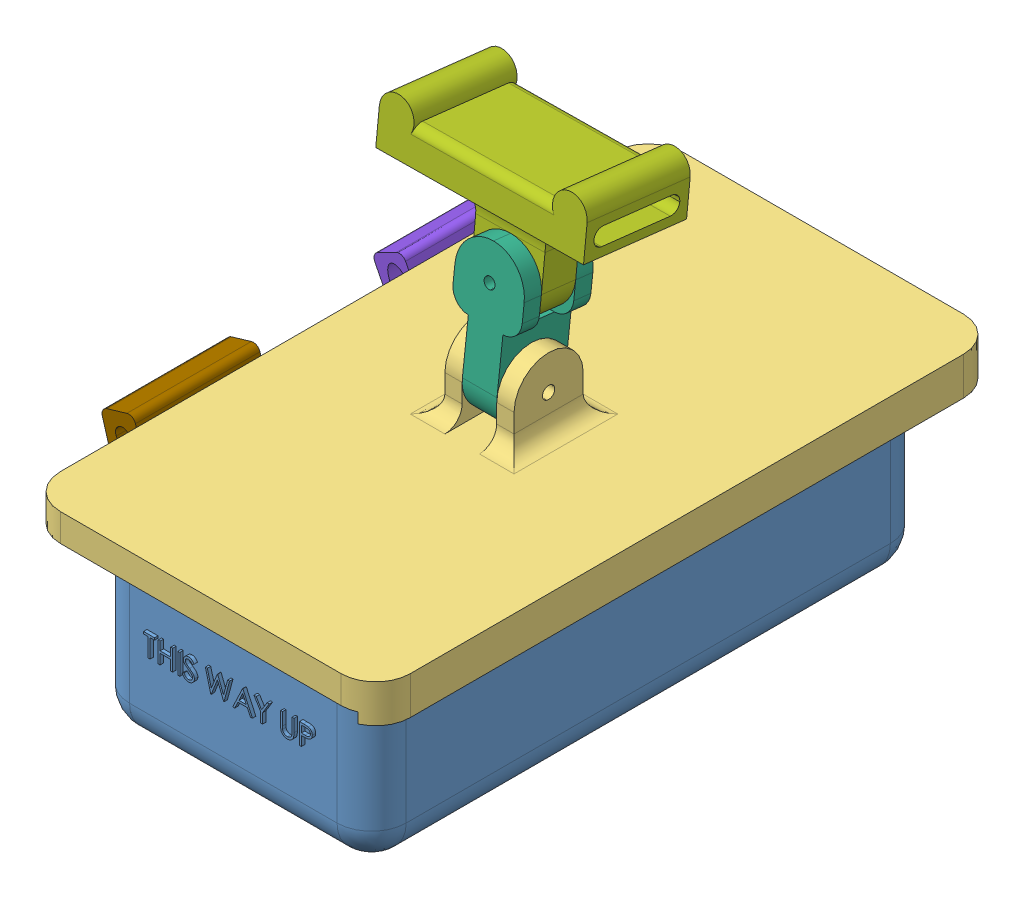
SolidWorks assembly Enclosure_2, configuration Default. Lengths in mm.
Overall size (143.75 176.14 228.6).
95 component instances, 27 part files, 36 mates.
Components (placement in the parent):
- Case-2: Case [Default] at (-101.6 0 -203.2) x (0 0 1) z (0 1 0) size (222.25 128.91 71.12)
- Battery Mockup-1: Battery Mockup [Default] at (-90.805 45.72 -177.165) x (0 0 1) z (-1 0 0) size (171.45 22.86 80.01)
- Lid-1: Lid [Default] at (14.2 73.66 12.7) x (-1 0 0) z (0 0 1) size (133.58 39.88 228.6)
- Camera Bracket-1: Camera Bracket [Default] at (-25.4 2.54 -66.675) x (0 0 -1) z (1 0 0) size (50.8 7.62 50.8)
- Separator-1: Separator [Default] at (-3.175 45.72 -3.175) x (0 -1 0) z (1 0 0) size (2.54 196.85 95.25)
- Cam V2.1 v1.step-1: Cam V2.1 v1.step [Default] at (-51.73 11.16 -89.4159) x (0 -1 0) z (1 0 0) size (6.48 24.01 25.01)
- RapberryPiZero.STEP-1: RapberryPiZero.STEP [Default] at (-102.4814 -13.0566 -128.6208) x (-1 0 0) z (0 0 -1) size (65 4.45 31.23)
  - Raspberry_pizero_PCB.STEP-1: Raspberry_pizero_PCB.STEP [Default] at (-51.2564 20.0966 13.0542) size (65 1 30)
  - Micro USB_input_female (short)-SMT.STEP-1: Micro USB_input_female (short)-SMT.STEP [Default] at (-42.3564 22.3216 26.5042) size (7.98 2.94 5.43)
  - Micro USB_input_female (short)-SMT.STEP-2: Micro USB_input_female (short)-SMT.STEP [Default] at (-29.7564 22.3216 26.5042) size (7.98 2.94 5.43)
  - 0204 - Capacitor.STEP-1: 0204 - Capacitor.STEP [Default] at (-62.4121 21.3466 11.2398) size (1 0.5 0.6)
  - 0204 - Capacitor.STEP-2: 0204 - Capacitor.STEP [Default] at (-62.4121 21.3466 12.2528) size (1 0.5 0.6)
  - 0204 - Capacitor.STEP-3: 0204 - Capacitor.STEP [Default] at (-61.8122 21.3466 13.3136) size (1 0.5 0.6)
  - 0204 - Capacitor.STEP-4: 0204 - Capacitor.STEP [Default] at (-61.8122 21.3466 14.2646) size (1 0.5 0.6)
  - 0204 - Capacitor.STEP-5: 0204 - Capacitor.STEP [Default] at (-61.8122 21.3466 15.241) size (1 0.5 0.6)
  - 0204 - Capacitor.STEP-6: 0204 - Capacitor.STEP [Default] at (-61.8122 21.3466 16.2144) size (1 0.5 0.6)
  - 0204 - Capacitor.STEP-7: 0204 - Capacitor.STEP [Default] at (-61.8122 21.3466 17.2416) size (1 0.5 0.6)
  - 0204 - Capacitor.STEP-8: 0204 - Capacitor.STEP [Default] at (-62.5919 21.3466 20.9695) size (1 0.5 0.6)
  - 0204 - Capacitor.STEP-9: 0204 - Capacitor.STEP [Default] at (-62.5919 21.3466 21.919) size (1 0.5 0.6)
  - 0204 - Capacitor.STEP-10: 0204 - Capacitor.STEP [Default] at (-60.4584 21.3466 22.3712) x (0 0 1) z (-1 0 0) size (1 0.5 0.6)
  - 0204 - Capacitor.STEP-11: 0204 - Capacitor.STEP [Default] at (-60.0807 21.3466 22.3712) x (0 0 -1) z (1 0 0) size (1 0.5 0.6)
  - 0204 - Capacitor.STEP-12: 0204 - Capacitor.STEP [Default] at (-59.0466 21.3466 22.3712) x (0 0 -1) z (1 0 0) size (1 0.5 0.6)
  - 0204 - Capacitor.STEP-13: 0204 - Capacitor.STEP [Default] at (-52.6496 21.3466 22.316) x (0 0 1) z (-1 0 0) size (1 0.5 0.6)
  - 0204 - Capacitor.STEP-14: 0204 - Capacitor.STEP [Default] at (-52.25 21.3466 22.316) x (0 0 -1) z (1 0 0) size (1 0.5 0.6)
  - 0204 - Capacitor.STEP-15: 0204 - Capacitor.STEP [Default] at (-51.2398 21.3466 22.316) x (0 0 -1) z (1 0 0) size (1 0.5 0.6)
  - 0204 - Capacitor.STEP-16: 0204 - Capacitor.STEP [Default] at (-49.1841 21.3466 22.316) x (0 0 -1) z (1 0 0) size (1 0.5 0.6)
  - 0204 - Capacitor.STEP-17: 0204 - Capacitor.STEP [Default] at (-48.1448 21.3466 22.316) x (0 0 -1) z (1 0 0) size (1 0.5 0.6)
  - 0204 - Capacitor.STEP-18: 0204 - Capacitor.STEP [Default] at (-46.475 21.3466 21.113) size (1 0.5 0.6)
  - 0204 - Capacitor.STEP-19: 0204 - Capacitor.STEP [Default] at (-45.7322 21.3466 20.0663) size (1 0.5 0.6)
  - 0204 - Capacitor.STEP-20: 0204 - Capacitor.STEP [Default] at (-45.7322 21.3466 19.0675) size (1 0.5 0.6)
  - 0204 - Capacitor.STEP-21: 0204 - Capacitor.STEP [Default] at (-45.7322 21.3466 18.1249) size (1 0.5 0.6)
  - 0204 - Capacitor.STEP-22: 0204 - Capacitor.STEP [Default] at (-45.7322 21.3466 17.1095) size (1 0.5 0.6)
  - 0204 - Capacitor.STEP-23: 0204 - Capacitor.STEP [Default] at (-46.3457 21.3466 16.1412) size (1 0.5 0.6)
  - 0204 - Capacitor.STEP-24: 0204 - Capacitor.STEP [Default] at (-46.3457 21.3466 15.1229) size (1 0.5 0.6)
  - 0204 - Capacitor.STEP-25: 0204 - Capacitor.STEP [Default] at (-46.3457 21.3466 14.0197) size (1 0.5 0.6)
  - 0204 - Capacitor.STEP-26: 0204 - Capacitor.STEP [Default] at (-46.3457 21.3466 12.9589) size (1 0.5 0.6)
  - 0204 - Capacitor.STEP-27: 0204 - Capacitor.STEP [Default] at (-43.6156 21.3466 13.1418) size (1 0.5 0.6)
  - 0204 - Capacitor.STEP-28: 0204 - Capacitor.STEP [Default] at (-43.6156 21.3466 10.1424) size (1 0.5 0.6)
  - 0204 - Capacitor.STEP-29: 0204 - Capacitor.STEP [Default] at (-48.9117 21.3466 7.6917) size (1 0.5 0.6)
  - 0204 - Capacitor.STEP-30: 0204 - Capacitor.STEP [Default] at (-55.4926 21.3466 7.2526) x (0 0 -1) z (1 0 0) size (1 0.5 0.6)
  - 0204 - Capacitor.STEP-31: 0204 - Capacitor.STEP [Default] at (-53.7932 21.3466 7.2526) x (0 0 1) z (-1 0 0) size (1 0.5 0.6)
  - 0204 - Capacitor.STEP-32: 0204 - Capacitor.STEP [Default] at (-59.8477 21.3466 7.2526) x (0 0 1) z (-1 0 0) size (1 0.5 0.6)
  - 0204- Resistor.STEP-1: 0204- Resistor.STEP [Default] at (-43.6109 21.4522 15.4193) x (-1 0 0) z (0 -1 0) size (0.99 0.51 0.36)
  - 0204- Resistor.STEP-2: 0204- Resistor.STEP [Default] at (-43.6109 21.4522 14.4127) x (-1 0 0) z (0 -1 0) size (0.99 0.51 0.36)
  - 0204- Resistor.STEP-3: 0204- Resistor.STEP [Default] at (-43.6109 21.4522 12.4047) x (-1 0 0) z (0 -1 0) size (0.99 0.51 0.36)
  - 0204- Resistor.STEP-4: 0204- Resistor.STEP [Default] at (-42.6936 21.4522 18.4076) x (-1 0 0) z (0 -1 0) size (0.99 0.51 0.36)
  - 0204- Resistor.STEP-5: 0204- Resistor.STEP [Default] at (-39.831 21.4522 18.1462) x (0 0 1) z (0 -1 0) size (0.99 0.51 0.36)
  - 0204- Resistor.STEP-6: 0204- Resistor.STEP [Default] at (-61.8169 21.4522 19.8533) x (-1 0 0) z (0 -1 0) size (0.99 0.51 0.36)
  - 0204- Resistor.STEP-7: 0204- Resistor.STEP [Default] at (-61.8169 21.4522 18.5178) x (-1 0 0) z (0 -1 0) size (0.99 0.51 0.36)
  - 0204- Resistor.STEP-8: 0204- Resistor.STEP [Default] at (-79.148 21.4522 17.7279) x (-1 0 0) z (0 -1 0) size (0.99 0.51 0.36)
  - 0204- Resistor.STEP-9: 0204- Resistor.STEP [Default] at (-56.0985 21.4522 7.2479) x (0 0 -1) z (0 -1 0) size (0.99 0.51 0.36)
  - 0204- Resistor.STEP-10: 0204- Resistor.STEP [Default] at (-28.0827 21.4522 9.5819) x (-1 0 0) z (0 -1 0) size (0.99 0.51 0.36)
  - 0204- Resistor.STEP-11: 0204- Resistor.STEP [Default] at (-21.8613 21.4522 20.9026) x (-1 0 0) z (0 -1 0) size (0.99 0.51 0.36)
  - CAP-0306.STEP-1: CAP-0306.STEP [Default] at (-45.8903 21.4966 8.7634) size (1.6 0.8 0.9)
  - CAP-0306.STEP-2: CAP-0306.STEP [Default] at (-82.0031 21.4966 19.0464) x (0 0 1) z (-1 0 0) size (1.6 0.8 0.9)
  - Raspberry_pizero_BCM2835 with VC4.STEP-1: Raspberry_pizero_BCM2835 with VC4.STEP [Default] at (-54.1608 21.5466 15.1238) x (1 0 0) z (0 0 -1) size (12 0.65 12)
  - Crystal 3.4x2.4mm.STEP-1: Crystal 3.4x2.4mm.STEP [Default] at (-65.3089 21.0966 19.2633) size (3.2 1 2.4)
  - 0204- Resistor.STEP-12: 0204- Resistor.STEP [Default] at (-68.4329 21.4522 5.4384) x (0 0 1) z (0 -1 0) size (0.99 0.51 0.36)
  - 0204- Resistor.STEP-13: 0204- Resistor.STEP [Default] at (-69.7255 21.4522 5.4384) x (0 0 1) z (0 -1 0) size (0.99 0.51 0.36)
  - 0204- Resistor.STEP-14: 0204- Resistor.STEP [Default] at (-65.0626 21.4522 16.5355) x (1 0 0) z (0 -1 0) size (0.99 0.51 0.36)
  - 32,768 Khz Crystal.STEP-1: 32,768 Khz Crystal.STEP [Default] at (-60.5154 21.1428 26.5473) x (0.999848 -0.017452 0) z (0 0 1) size (3.4 1.03 1.5)
  - 0805- Capacitor.STEP-1: 0805- Capacitor.STEP [Default] at (-51.9496 21.9966 5.2384) x (1 0 0) z (0 -1 0) size (2 1.26 0.91)
  - 0805- Capacitor.STEP-2: 0805- Capacitor.STEP [Default] at (-51.9496 21.9966 7.3589) x (1 0 0) z (0 -1 0) size (2 1.26 0.91)
  - 0805- Capacitor.STEP-3: 0805- Capacitor.STEP [Default] at (-37.009 21.9966 22.5384) x (0 0 -1) z (0 -1 0) size (2 1.26 0.91)
  - 0805- Capacitor.STEP-4: 0805- Capacitor.STEP [Default] at (-29.8247 21.9966 13.3538) x (0 0 1) z (0 -1 0) size (2 1.26 0.91)
  - 0805- Capacitor.STEP-5: 0805- Capacitor.STEP [Default] at (-27.9052 21.9966 13.3538) x (0 0 -1) z (0 -1 0) size (2 1.26 0.91)
  - 0805- Capacitor.STEP-6: 0805- Capacitor.STEP [Default] at (-22.8003 21.9966 13.3538) x (0 0 -1) z (0 -1 0) size (2 1.26 0.91)
  - 0805- Capacitor.STEP-7: 0805- Capacitor.STEP [Default] at (-20.9924 21.9966 13.3538) x (0 0 -1) z (0 -1 0) size (2 1.26 0.91)
  - 0204- Resistor.STEP-15: 0204- Resistor.STEP [Default] at (-48.8769 21.4522 23.8207) x (1 0 0) z (0 -1 0) size (0.99 0.51 0.36)
  - 0204- Resistor.STEP-16: 0204- Resistor.STEP [Default] at (-52.4165 21.4522 24.0419) x (1 0 0) z (0 -1 0) size (0.99 0.51 0.36)
  - 0204 - Capacitor.STEP-33: 0204 - Capacitor.STEP [Default] at (-47.1199 21.3466 23.926) x (0 0 1) z (-1 0 0) size (1 0.5 0.6)
  - 0204 - Capacitor Brown.STEP-1: 0204 - Capacitor Brown.STEP [Default] at (-57.5817 21.3466 26.803) size (1 0.5 0.6)
  - 0204 - Capacitor Brown.STEP-2: 0204 - Capacitor Brown.STEP [Default] at (-64.0312 21.3466 26.8794) size (1 0.5 0.6)
  - 0204 - Capacitor Brown.STEP-3: 0204 - Capacitor Brown.STEP [Default] at (-46.3457 21.3466 12.214) size (1 0.5 0.6)
  - 0204 - Capacitor Brown.STEP-4: 0204 - Capacitor Brown.STEP [Default] at (-46.3457 21.3466 11.0963) size (1 0.5 0.6)
  - 0204 - Capacitor Brown.STEP-5: 0204 - Capacitor Brown.STEP [Default] at (-46.3457 21.3466 10.1566) size (1 0.5 0.6)
  - 0204 - Capacitor Brown.STEP-6: 0204 - Capacitor Brown.STEP [Default] at (-43.6156 21.3466 11.1151) size (1 0.5 0.6)
  - 0204 - Capacitor Brown.STEP-7: 0204 - Capacitor Brown.STEP [Default] at (-28.0874 21.3466 10.3236) size (1 0.5 0.6)
  - 0204 - Capacitor Brown.STEP-8: 0204 - Capacitor Brown.STEP [Default] at (-80.6197 21.3466 20.6997) size (1 0.5 0.6)
  - 0204- Resistor.STEP-17: 0204- Resistor.STEP [Default] at (-78.9105 21.4522 21.1554) x (1 0 0) z (0 -1 0) size (0.99 0.51 0.36)
  - 6-Pin SOT.STEP-1: 6-Pin SOT.STEP [Default] at (-79.714 21.0966 19.2138) x (0 0 1) z (0 1 0) size (1.5 1.84 0.95)
  - micro sd molex.STEP-1: micro sd molex.STEP [Default] at (-74.7768 21.6766 -33.0961) x (0 0 1) z (0 1 0) size (11.95 11.4 1.45)
  - hdmi type C.STEP-1: hdmi type C.STEP [Default] at (-71.3564 22.9466 28.6542) size (12.9 4.05 7.7)
  - Voltage Regulator 3x3mm 12-Pin.STEP-1: Voltage Regulator 3x3mm 12-Pin.STEP [Default] at (-23.6842 21.0966 12.6105) x (1 0 0) z (0 1 0) size (3 4.1 1.2)
  - 1210 inductor.STEP-1: 1210 inductor.STEP [Default] at (-46.4963 21.0916 6.3909) x (0 0 1) z (0 1 0) size (3.26 2.79 0.75)
  - 1210 inductor.STEP-2: 1210 inductor.STEP [Default] at (-22.7405 21.0916 9.2394) x (1 0 0) z (0 1 0) size (3.26 2.79 0.75)
  - 1210 inductor.STEP-3: 1210 inductor.STEP [Default] at (-28.2854 21.0916 17.6682) x (1 0 0) z (0 1 0) size (3.26 2.79 0.75)
  - 0204 - Capacitor.STEP-34: 0204 - Capacitor.STEP [Default] at (-48.9117 21.3466 6.5273) size (1 0.5 0.6)
- HCSR501.step-1: HCSR501.step [Default] at (-50.8 6.08 -41.275) x (-1 0 0) z (0 -1 0) size (32 25 25.1)
- Latch-1: Latch [Default] at (-117.1107 62.675 -33.02) x (0.048133 -0.998841 0) z (0 0 1) size (36.83 11.74 35.56)
- Latch-2: Latch [Default] at (-118.5221 61.2748 -134.62) x (0.332187 -0.943213 0) z (0 0 1) size (36.83 11.74 35.56)
- Swivel-1: Swivel [Default] at (-55.65 86.8687 -101.6) x (0 0.993442 -0.114338) z (1 0 0) size (57.15 25.4 25.4)
- Mount-1: Mount [Default] at (-49.3 117.6845 -111.5386) x (-0.00983 0.993394 -0.114332) z (0 0.114338 0.993442) size (57.15 76.2 38.1)
- Hook_Design1-1: Hook_Design1 [Default] at (-104.4857 49.427 -129.54) x (-0.892928 -0.4502 0) z (0 0 -1) size (12.7 30.48 45.72)
- Hook-2: Hook [Default] at (-106.6984 47.961 -27.94) x (-0.958568 -0.284865 0) z (0 0 -1) size (12.7 30.48 45.72)
Mates (geometry in assembly coordinates):
- Distance1: distance = 2.54 mm anti-aligned: plane of Battery Mockup-1 through (-90.805 68.58 -5.715) normal (0 0 1); plane of Top_001-2 through (-98.425 2.54 -3.175) normal (0 0 -1)
- Coincident1: coincident anti-aligned: plane of Top_001-2 through (-98.425 71.12 -3.175) normal (0 1 0); plane of Lid-1 through (1.5 71.12 0) normal (0 -1 0)
- Distance2: distance = 0.635 mm anti-aligned: plane of Bottom_001-1 through (-111.76 63.5 -200.66) normal (1 0 0); plane of Top_001-2 through (-111.125 71.12 -200.025) normal (-1 0 0)
- Distance3: distance = 0.635 mm anti-aligned: plane of Bottom_001-1 through (-1.04 63.5 -213.36) normal (0 0 1); plane of Top_001-2 through (-3.175 71.12 -212.725) normal (0 0 -1)
- Coincident4: coincident anti-aligned: plane of Top_001-2 through (-101.6 2.54 -203.2) normal (0 1 0); plane of Camera Bracket-1 through (-31.75 2.54 -111.125) normal (0 -1 0)
- Coincident5: coincident anti-aligned: plane of Top_001-2 through (-85.725 43.18 -187.325) normal (0 1 0); plane of Separator-1 through (-15.875 43.18 -15.875) normal (0 -1 0)
- Concentric3: concentric anti-aligned: cylinder of Top_001-2 through (-85.725 2.54 -15.875) axis (0 -1 0) radius 12.7; cylinder of Separator-1 through (-85.725 43.18 -15.875) axis (0 1 0) radius 12.7
- Concentric4: concentric anti-aligned: cylinder of Top_001-2 through (-15.875 2.54 -15.875) axis (0 -1 0) radius 12.7; cylinder of Separator-1 through (-15.875 43.18 -15.875) axis (0 1 0) radius 12.7
- Distance4: distance = 7.62 mm anti-aligned: plane of Battery Mockup-1 through (-10.795 68.58 -177.165) normal (1 0 0); plane of Top_001-2 through (-3.175 2.54 -200.025) normal (-1 0 0)
- Coincident7: coincident anti-aligned: plane of Battery Mockup-1 through (-90.805 45.72 -177.165) normal (0 -1 0); plane of Separator-1 through (-15.875 45.72 -15.875) normal (0 1 0)
- Concentric5: concentric aligned: cylinder of Top_001-2 through (-31.75 6.985 -73.025) axis (0 -1 0) radius 2; cylinder of Camera Bracket-1 through (-31.75 10.16 -73.025) axis (0 -1 0) radius 1.5
- Concentric6: concentric aligned: cylinder of Top_001-2 through (-69.85 6.985 -73.025) axis (0 -1 0) radius 2; cylinder of Camera Bracket-1 through (-69.85 10.16 -73.025) axis (0 -1 0) radius 1.5
- Concentric12: concentric anti-aligned: cylinder of Top_001-2 through (-50.8 6.35 -41.275) axis (0 -1 0) radius 12.065; cylinder of HCSR501.step-1 through (-50.8 -0.8505 -41.275) axis (0 1 0) radius 11.4228
- Parallel3: parallel anti-aligned: plane of Top_001-2 through (-3.175 2.54 -200.025) normal (-1 0 0); plane of HCSR501.step-1 through (-34.8 6.08 -28.775) normal (1 0 0)
- Coincident12: coincident anti-aligned: plane of Top_001-2 through (-43.815 5.08 -41.275) normal (0 1 0); plane of HCSR501.step-1 through (-51.2586 5.08 -41.0657) normal (0 -1 0)
- Concentric14: concentric anti-aligned: cylinder of Top_001-2 through (-113.03 57.15 9.525) axis (0 0 -1) radius 1.5; cylinder of Latch-1 through (-113.03 57.15 -68.58) axis (0 0 1) radius 1.5
- Coincident13: coincident anti-aligned: plane of Top_001-2 through (-119.38 63.5 -38.1) normal (0 0 1); plane of Latch-1 through (-109.4995 63.0418 -38.1) normal (0 0 -1)
- Concentric15: concentric anti-aligned: circle of Top_001-2; cylinder of Latch-2 through (-113.03 57.15 -170.18) axis (0 0 1) radius 1.5
- Coincident14: coincident anti-aligned: plane of Top_001-2 through (-119.38 63.5 -165.1) normal (0 0 -1); plane of Latch-2 through (-111.3348 63.8061 -165.1) normal (0 0 1)
- Concentric16: concentric anti-aligned: cylinder of Camera Bracket-1 through (-62.23 2.54 -86.9159) axis (0 1 0) radius 1; cylinder of Cam V2.1 v1.step-1 through (-62.23 11.16 -86.9159) axis (0 -1 0) radius 1
- Concentric17: concentric anti-aligned: cylinder of Camera Bracket-1 through (-62.23 2.54 -99.4159) axis (0 1 0) radius 1; cylinder of Cam V2.1 v1.step-1 through (-62.23 11.16 -99.4159) axis (0 -1 0) radius 1
- Coincident15: coincident anti-aligned: plane of Camera Bracket-1 through (-31.75 10.16 -111.125) normal (0 1 0); plane of Cam V2.1 v1.step-1 through (-51.73 10.16 -89.4159) normal (0 -1 0)
- Concentric18: concentric anti-aligned: cylinder of Lid-1 through (-62 86.8687 -101.6) axis (1 0 0) radius 2.25; cylinder of Swivel-1 through (-42.95 86.8687 -101.6) axis (-1 0 0) radius 2.25
- Coincident16: coincident anti-aligned: plane of Lid-1 through (-55.65 73.66 -114.3) normal (1 0 0); plane of Swivel-1 through (-55.65 86.8687 -101.6) normal (-1 0 0)
- Concentric19: concentric aligned: cylinder of Swivel-1 through (-49.3 119.8626 -92.6135) axis (0 -0.114338 -0.993442) radius 12.7; cylinder of Mount-1 through (-49.3 119.1366 -98.9219) axis (0 -0.114338 -0.993442) radius 12.7
- Coincident17: coincident anti-aligned: plane of Swivel-1 through (-62 131.7533 -100.374) normal (0 -0.114338 -0.993442); plane of Mount-1 through (-49.3 119.1366 -98.9219) normal (0 0.114338 0.993442)
- Concentric20: concentric aligned: cylinder of Latch-1 through (-112.7244 50.8074 -68.58) axis (0 0 1) radius 1.6; cylinder of Upper Latch-2 through (-112.7244 50.8074 -73.66) axis (0 0 1) radius 1.5
- Coincident18: coincident anti-aligned: plane of Latch-1 through (-109.4995 63.0418 -68.58) normal (0 0 -1); plane of Upper Latch-2 through (-94.5246 51.5788 -68.58) normal (0 0 1)
- Concentric21: concentric aligned: cylinder of Latch-2 through (-110.9206 51.1606 -170.18) axis (0 0 1) radius 1.6; cylinder of Hook_Design1-1 through (-110.9206 51.1606 -175.26) axis (0 0 1) radius 1.5
- Coincident19: coincident anti-aligned: plane of Latch-2 through (-111.3348 63.8061 -134.62) normal (0 0 1); plane of Hook_Design1-1 through (-93.1455 55.1445 -134.62) normal (0 0 -1)
- Concentric22: concentric aligned: cylinder of Top_001-2 through (-80.225 7.04 -130.175) axis (0 -1 0) radius 2; cylinder of RapberryPiZero.STEP-1/Raspberry_pizero_PCB.STEP-1 through (-80.225 8.04 -130.175) axis (0 -1 0) radius 1.375
- Concentric23: concentric aligned: cylinder of Top_001-2 through (-22.225 7.04 -153.175) axis (0 -1 0) radius 2; cylinder of RapberryPiZero.STEP-1/Raspberry_pizero_PCB.STEP-1 through (-22.225 8.04 -153.175) axis (0 -1 0) radius 1.375
- Coincident20: coincident anti-aligned: plane of Top_001-2 through (-101.6 7.04 -203.2) normal (0 1 0); plane of RapberryPiZero.STEP-1/Raspberry_pizero_PCB.STEP-1 through (-21.725 7.04 -129.675) normal (0 -1 0)
- Coincident21: coincident anti-aligned: plane of Top_001-2 through (-101.6 0 -203.2) normal (0 -1 0)
- Coincident22: coincident aligned: plane of Top_001-2 through (0 63.5 -203.2) normal (1 0 0)
- Coincident23: coincident aligned: plane of Top_001-2 through (-101.6 63.5 0) normal (0 0 1)
